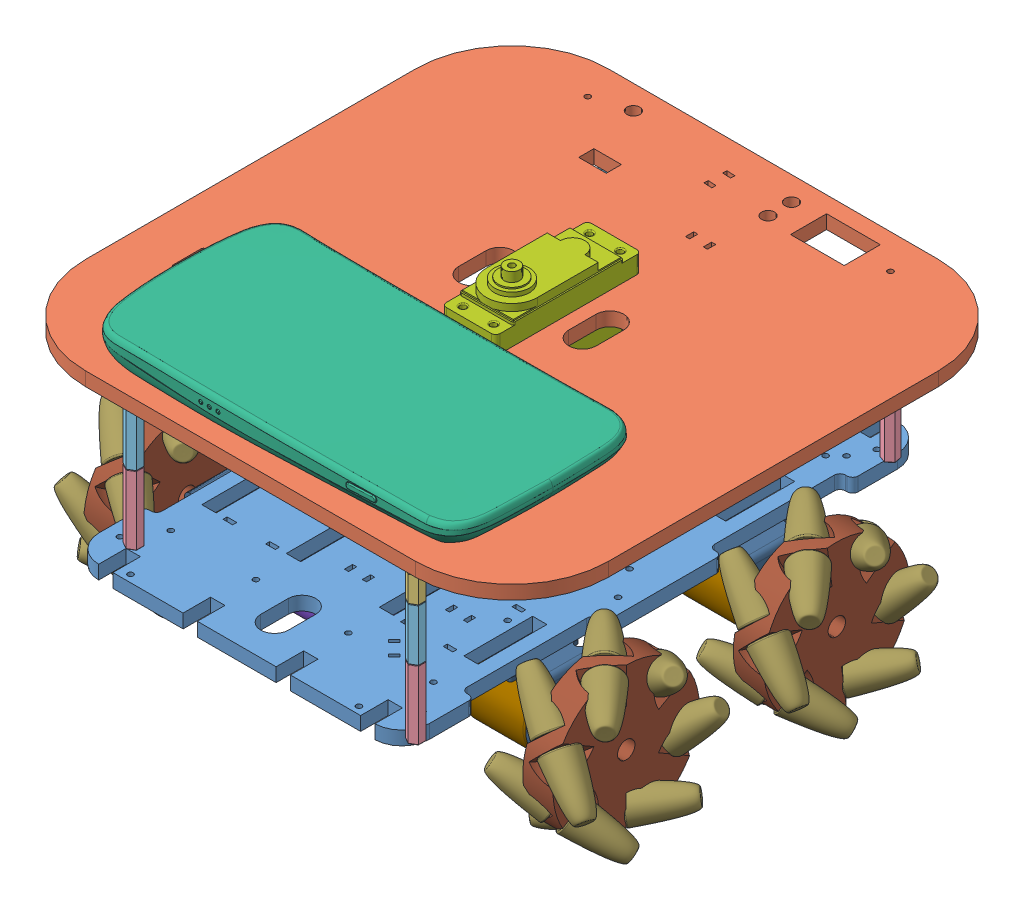
SolidWorks assembly Robo_01, configuration Valor predeterminado. Lengths in mm.
Overall size (202.63 132.58 190.5).
92 component instances, 12 part files, 61 mates.
Components (placement in the parent):
- Plataforma_1-1: Plataforma_1 [Valor predeterminado] at (-69.9818 -54.6704 16.9892) size (120 5 190)
- Plataforma_2-1: Plataforma_2 [Valor predeterminado] at (-104.9818 3.8296 16.9892) size (190 5 190)
- PC-Standoff - 9.5mm - FF-1: PC-Standoff - 9.5mm - FF [Valor predeterminado] at (-59.9818 -5.6704 -0.5108) x (0.866025 0 0.5) z (-0.5 0 0.866025) size (5.5 9.5 4.76)
- PC-Standoff - 9.5mm - FF-2: PC-Standoff - 9.5mm - FF [Valor predeterminado] at (52.5182 -5.6704 9.4892) x (0 0 1) z (-1 0 0) size (5.5 9.5 4.76)
- PC-Standoff - 9.5mm - FF-3: PC-Standoff - 9.5mm - FF [Valor predeterminado] at (-62.4818 -5.6704 -175.5108) x (0 0 1) z (-1 0 0) size (5.5 9.5 4.76)
- PC-Standoff - 9.5mm - FF-4: PC-Standoff - 9.5mm - FF [Valor predeterminado] at (50.0182 -5.6704 -165.5108) x (0.176181 0 0.984358) z (-0.984358 0 0.176181) size (5.5 9.5 4.76)
- PC-Standoff - 25mm-6: PC-Standoff - 25mm [Valor predeterminado] at (50.0182 -24.6704 -165.5108) x (-0.176181 0 -0.984358) z (-0.984358 0 0.176181) size (5.5 29.76 4.76)
- PC-Standoff - 19mm-6: PC-Standoff - 19mm [Valor predeterminado] at (50.0182 -5.6704 -165.5108) x (-0.176181 0 -0.984358) z (-0.984358 0 0.176181) size (5.5 23.76 4.76)
- PC-Standoff - 25mm-7: PC-Standoff - 25mm [Valor predeterminado] at (52.5182 -24.6704 9.4892) x (0 0 -1) z (-1 0 0) size (5.5 29.76 4.76)
- PC-Standoff - 19mm-7: PC-Standoff - 19mm [Valor predeterminado] at (52.5182 -5.6704 9.4892) x (0 0 -1) z (-1 0 0) size (5.5 23.76 4.76)
- PC-Standoff - 25mm-8: PC-Standoff - 25mm [Valor predeterminado] at (-59.9818 -24.6704 -0.5108) x (0 0 -1) z (-1 0 0) size (5.5 29.76 4.76)
- PC-Standoff - 19mm-8: PC-Standoff - 19mm [Valor predeterminado] at (-59.9818 -5.6704 -0.5108) x (0 0 -1) z (-1 0 0) size (5.5 23.76 4.76)
- PC-Standoff - 19mm-1: PC-Standoff - 19mm [Valor predeterminado] at (-62.4818 -5.6704 -175.5108) x (0 0 -1) z (-1 0 0) size (5.5 23.76 4.76)
- PC-Standoff - 25mm-1: PC-Standoff - 25mm [Valor predeterminado] at (-62.4818 -24.6704 -175.5108) x (0 0 -1) z (-1 0 0) size (5.5 29.76 4.76)
- Nexus-1: Nexus [Default] at (-34.6431 -20.5856 4.0062) x (0.001932 0 0.999998) z (0 1 0) size (78.79 147.01 23.11)
- Servo-HS-311-1: Servo-HS-311 [Default] at (5.0182 -16.5704 -73.4788) x (0 0 -1) z (1 0 0) size (52.83 41.27 19.56)
- Motor_com_suporte-1: Motor_com_suporte [Valor predeterminado] at (-43.7296 -69.2683 -124.4885) x (0 -0.561689 -0.827349) z (-1 0 0) size (35.57 35.97 69.3)
  - Motor-2: Motor [Valor predeterminado] at (3.672 0.435 -26.0477) size (25 25 69.3)
    - Motor-1: Motor [Valor predeterminado] at (-6.4714 0.7429 0) size (24.4 24.4 45.8)
    - Motor_Redutor-1: Motor_Redutor [Valor predeterminado] at (-6.4714 0.7429 30.8) size (25 25 33.5)
  - Suporte_Motor-1: Suporte_Motor [Valor predeterminado] at (-21.0049 -3.3839 29.2523) x (0.827349 -0.561689 0) z (0 0 1) size (25 26.5 51.5)
- Mecanum-1: Mecanum [Valor predeterminado] at (-89.6759 -62.9091 -126.9148) x (0 0.729357 -0.684133) z (0 -0.684133 -0.729357) size (63.95 43.87 68.72)
  - Mecanum_meio-1: Mecanum_meio [Valor predeterminado] at (-7.8992 -5.806 0) size (53.2 11 53.2)
  - Mecanum_wheel-1: Mecanum_wheel [Valor predeterminado] at (-15.5494 1.6585 20.3217) x (0.789069 -0.574225 -0.218256) z (-0.048689 -0.412632 0.909596) size (12.32 20.06 12.32)
  - Mecanum_wheel-2: Mecanum_wheel [Valor predeterminado] at (-29.3234 1.6585 3.5355) x (0.985157 -0.121379 0.121379) z (-0.171655 -0.696611 0.696611) size (12.32 20.06 12.32)
  - Mecanum_wheel-3: Mecanum_wheel [Valor predeterminado] at (-21.6732 1.6585 -16.7862) x (0.789069 0.51914 0.328426) z (-0.048689 -0.480097 0.875863) size (12.32 20.06 12.32)
  - Mecanum_wheel-4: Mecanum_wheel [Valor predeterminado] at (-0.2489 1.6585 -20.3217) x (0.789069 0.574225 -0.218256) z (-0.048689 0.412632 0.909596) size (12.32 20.06 12.32)
  - Mecanum_wheel-5: Mecanum_wheel [Valor predeterminado] at (13.5251 1.6585 -3.5355) x (0.91238 -0.28945 -0.28945) z (0.409344 0.64515 0.64515) size (12.32 20.06 12.32)
  - Mecanum_wheel-6: Mecanum_wheel [Valor predeterminado] at (5.8748 1.6585 16.7862) x (0.68106 -0.698943 -0.218256) z (0.401444 0.107137 0.909596) size (12.32 20.06 12.32)
  - Mecanum_wheel-8: Mecanum_wheel [Valor predeterminado] at (-29.3234 -1.5235 0.3536) x (1 0 0) z (0 0.707107 -0.707107) size (12.32 20.06 12.32)
  - Mecanum_wheel-9: Mecanum_wheel [Valor predeterminado] at (-18.3051 -1.5235 18.7308) x (0.785714 -0.494872 -0.371154) z (-0.087482 0.505076 -0.85863) size (12.32 20.06 12.32)
  - Mecanum_wheel-10: Mecanum_wheel [Valor predeterminado] at (3.1192 -1.5235 18.3772) x (0.7 -0.69282 -0.173205) z (-0.367423 -0.141421 -0.919239) size (12.32 20.06 12.32)
  - Mecanum_wheel-11: Mecanum_wheel [Valor predeterminado] at (13.5251 -1.5235 -0.3536) x (1 0 0) z (0 -0.707107 -0.707107) size (12.32 20.06 12.32)
  - Mecanum_wheel-12: Mecanum_wheel [Valor predeterminado] at (2.5068 -1.5235 -18.7308) x (0.7 0.69282 0.173205) z (0.367423 -0.141421 -0.919239) size (12.32 20.06 12.32)
  - Mecanum_wheel-13: Mecanum_wheel [Valor predeterminado] at (-18.9175 -1.5235 -18.3772) x (0.785714 0.494872 0.371154) z (0.087482 0.505076 -0.85863) size (12.32 20.06 12.32)
- Motor_com_suporte-2: Motor_com_suporte [Valor predeterminado] at (-43.7296 -69.2683 -47.4885) x (0 -0.561689 -0.827349) z (-1 0 0) size (35.57 35.97 69.3)
  - Motor-2: Motor [Valor predeterminado] at (3.672 0.435 -26.0477) size (25 25 69.3)
    - Motor-1: Motor [Valor predeterminado] at (-6.4714 0.7429 0) size (24.4 24.4 45.8)
    - Motor_Redutor-1: Motor_Redutor [Valor predeterminado] at (-6.4714 0.7429 30.8) size (25 25 33.5)
  - Suporte_Motor-1: Suporte_Motor [Valor predeterminado] at (-21.0049 -3.3839 29.2523) x (0.827349 -0.561689 0) z (0 0 1) size (25 26.5 51.5)
- Mecanum-2: Mecanum [Valor predeterminado] at (-89.6759 -66.4607 -52.0946) x (0 0.279735 -0.960077) z (0 -0.960077 -0.279735) size (63.95 43.87 68.72)
  - Mecanum_meio-1: Mecanum_meio [Valor predeterminado] at (-7.8992 -5.806 0) size (53.2 11 53.2)
  - Mecanum_wheel-1: Mecanum_wheel [Valor predeterminado] at (-15.5494 1.6585 20.3217) x (0.789069 -0.574225 -0.218256) z (-0.048689 -0.412632 0.909596) size (12.32 20.06 12.32)
  - Mecanum_wheel-2: Mecanum_wheel [Valor predeterminado] at (-29.3234 1.6585 3.5355) x (0.985157 -0.121379 0.121379) z (-0.171655 -0.696611 0.696611) size (12.32 20.06 12.32)
  - Mecanum_wheel-3: Mecanum_wheel [Valor predeterminado] at (-21.6732 1.6585 -16.7862) x (0.789069 0.51914 0.328426) z (-0.048689 -0.480097 0.875863) size (12.32 20.06 12.32)
  - Mecanum_wheel-4: Mecanum_wheel [Valor predeterminado] at (-0.2489 1.6585 -20.3217) x (0.789069 0.574225 -0.218256) z (-0.048689 0.412632 0.909596) size (12.32 20.06 12.32)
  - Mecanum_wheel-5: Mecanum_wheel [Valor predeterminado] at (13.5251 1.6585 -3.5355) x (0.91238 -0.28945 -0.28945) z (0.409344 0.64515 0.64515) size (12.32 20.06 12.32)
  - Mecanum_wheel-6: Mecanum_wheel [Valor predeterminado] at (5.8748 1.6585 16.7862) x (0.68106 -0.698943 -0.218256) z (0.401444 0.107137 0.909596) size (12.32 20.06 12.32)
  - Mecanum_wheel-8: Mecanum_wheel [Valor predeterminado] at (-29.3234 -1.5235 0.3536) x (1 0 0) z (0 0.707107 -0.707107) size (12.32 20.06 12.32)
  - Mecanum_wheel-9: Mecanum_wheel [Valor predeterminado] at (-18.3051 -1.5235 18.7308) x (0.785714 -0.494872 -0.371154) z (-0.087482 0.505076 -0.85863) size (12.32 20.06 12.32)
  - Mecanum_wheel-10: Mecanum_wheel [Valor predeterminado] at (3.1192 -1.5235 18.3772) x (0.7 -0.69282 -0.173205) z (-0.367423 -0.141421 -0.919239) size (12.32 20.06 12.32)
  - Mecanum_wheel-11: Mecanum_wheel [Valor predeterminado] at (13.5251 -1.5235 -0.3536) x (1 0 0) z (0 -0.707107 -0.707107) size (12.32 20.06 12.32)
  - Mecanum_wheel-12: Mecanum_wheel [Valor predeterminado] at (2.5068 -1.5235 -18.7308) x (0.7 0.69282 0.173205) z (0.367423 -0.141421 -0.919239) size (12.32 20.06 12.32)
  - Mecanum_wheel-13: Mecanum_wheel [Valor predeterminado] at (-18.9175 -1.5235 -18.3772) x (0.785714 0.494872 0.371154) z (0.087482 0.505076 -0.85863) size (12.32 20.06 12.32)
- Mecanum-7: Mecanum [Valor predeterminado] at (69.2122 -73.799 -38.5029) x (0 -0.649254 0.760572) z (0 -0.760572 -0.649254) size (63.95 43.87 68.72)
  - Mecanum_meio-1: Mecanum_meio [Valor predeterminado] at (-7.8992 -5.806 0) size (53.2 11 53.2)
  - Mecanum_wheel-1: Mecanum_wheel [Valor predeterminado] at (-15.5494 1.6585 20.3217) x (0.789069 -0.574225 -0.218256) z (-0.048689 -0.412632 0.909596) size (12.32 20.06 12.32)
  - Mecanum_wheel-2: Mecanum_wheel [Valor predeterminado] at (-29.3234 1.6585 3.5355) x (0.985157 -0.121379 0.121379) z (-0.171655 -0.696611 0.696611) size (12.32 20.06 12.32)
  - Mecanum_wheel-3: Mecanum_wheel [Valor predeterminado] at (-21.6732 1.6585 -16.7862) x (0.789069 0.51914 0.328426) z (-0.048689 -0.480097 0.875863) size (12.32 20.06 12.32)
  - Mecanum_wheel-4: Mecanum_wheel [Valor predeterminado] at (-0.2489 1.6585 -20.3217) x (0.789069 0.574225 -0.218256) z (-0.048689 0.412632 0.909596) size (12.32 20.06 12.32)
  - Mecanum_wheel-5: Mecanum_wheel [Valor predeterminado] at (13.5251 1.6585 -3.5355) x (0.91238 -0.28945 -0.28945) z (0.409344 0.64515 0.64515) size (12.32 20.06 12.32)
  - Mecanum_wheel-6: Mecanum_wheel [Valor predeterminado] at (5.8748 1.6585 16.7862) x (0.68106 -0.698943 -0.218256) z (0.401444 0.107137 0.909596) size (12.32 20.06 12.32)
  - Mecanum_wheel-8: Mecanum_wheel [Valor predeterminado] at (-29.3234 -1.5235 0.3536) x (1 0 0) z (0 0.707107 -0.707107) size (12.32 20.06 12.32)
  - Mecanum_wheel-9: Mecanum_wheel [Valor predeterminado] at (-18.3051 -1.5235 18.7308) x (0.785714 -0.494872 -0.371154) z (-0.087482 0.505076 -0.85863) size (12.32 20.06 12.32)
  - Mecanum_wheel-10: Mecanum_wheel [Valor predeterminado] at (3.1192 -1.5235 18.3772) x (0.7 -0.69282 -0.173205) z (-0.367423 -0.141421 -0.919239) size (12.32 20.06 12.32)
  - Mecanum_wheel-11: Mecanum_wheel [Valor predeterminado] at (13.5251 -1.5235 -0.3536) x (1 0 0) z (0 -0.707107 -0.707107) size (12.32 20.06 12.32)
  - Mecanum_wheel-12: Mecanum_wheel [Valor predeterminado] at (2.5068 -1.5235 -18.7308) x (0.7 0.69282 0.173205) z (0.367423 -0.141421 -0.919239) size (12.32 20.06 12.32)
  - Mecanum_wheel-13: Mecanum_wheel [Valor predeterminado] at (-18.9175 -1.5235 -18.3772) x (0.785714 0.494872 0.371154) z (0.087482 0.505076 -0.85863) size (12.32 20.06 12.32)
- Motor_com_suporte-7: Motor_com_suporte [Valor predeterminado] at (23.2659 -69.2683 -41.533) x (0 -0.561689 0.827349) z (1 0 0) size (35.57 35.97 69.3)
  - Motor-2: Motor [Valor predeterminado] at (3.672 0.435 -26.0477) size (25 25 69.3)
    - Motor-1: Motor [Valor predeterminado] at (-6.4714 0.7429 0) size (24.4 24.4 45.8)
    - Motor_Redutor-1: Motor_Redutor [Valor predeterminado] at (-6.4714 0.7429 30.8) size (25 25 33.5)
  - Suporte_Motor-1: Suporte_Motor [Valor predeterminado] at (-21.0049 -3.3839 29.2523) x (0.827349 -0.561689 0) z (0 0 1) size (25 26.5 51.5)
- Mecanum-11: Mecanum [Valor predeterminado] at (68.7122 -61.1594 -119.0649) x (0 0.950856 0.309633) z (0 -0.309633 0.950856) size (63.95 43.87 68.72)
  - Mecanum_meio-1: Mecanum_meio [Valor predeterminado] at (-7.8992 -5.806 0) size (53.2 11 53.2)
  - Mecanum_wheel-1: Mecanum_wheel [Valor predeterminado] at (-15.5494 1.6585 20.3217) x (0.789069 -0.574225 -0.218256) z (-0.048689 -0.412632 0.909596) size (12.32 20.06 12.32)
  - Mecanum_wheel-2: Mecanum_wheel [Valor predeterminado] at (-29.3234 1.6585 3.5355) x (0.985157 -0.121379 0.121379) z (-0.171655 -0.696611 0.696611) size (12.32 20.06 12.32)
  - Mecanum_wheel-3: Mecanum_wheel [Valor predeterminado] at (-21.6732 1.6585 -16.7862) x (0.789069 0.51914 0.328426) z (-0.048689 -0.480097 0.875863) size (12.32 20.06 12.32)
  - Mecanum_wheel-4: Mecanum_wheel [Valor predeterminado] at (-0.2489 1.6585 -20.3217) x (0.789069 0.574225 -0.218256) z (-0.048689 0.412632 0.909596) size (12.32 20.06 12.32)
  - Mecanum_wheel-5: Mecanum_wheel [Valor predeterminado] at (13.5251 1.6585 -3.5355) x (0.91238 -0.28945 -0.28945) z (0.409344 0.64515 0.64515) size (12.32 20.06 12.32)
  - Mecanum_wheel-6: Mecanum_wheel [Valor predeterminado] at (5.8748 1.6585 16.7862) x (0.68106 -0.698943 -0.218256) z (0.401444 0.107137 0.909596) size (12.32 20.06 12.32)
  - Mecanum_wheel-8: Mecanum_wheel [Valor predeterminado] at (-29.3234 -1.5235 0.3536) x (1 0 0) z (0 0.707107 -0.707107) size (12.32 20.06 12.32)
  - Mecanum_wheel-9: Mecanum_wheel [Valor predeterminado] at (-18.3051 -1.5235 18.7308) x (0.785714 -0.494872 -0.371154) z (-0.087482 0.505076 -0.85863) size (12.32 20.06 12.32)
  - Mecanum_wheel-10: Mecanum_wheel [Valor predeterminado] at (3.1192 -1.5235 18.3772) x (0.7 -0.69282 -0.173205) z (-0.367423 -0.141421 -0.919239) size (12.32 20.06 12.32)
  - Mecanum_wheel-11: Mecanum_wheel [Valor predeterminado] at (13.5251 -1.5235 -0.3536) x (1 0 0) z (0 -0.707107 -0.707107) size (12.32 20.06 12.32)
  - Mecanum_wheel-12: Mecanum_wheel [Valor predeterminado] at (2.5068 -1.5235 -18.7308) x (0.7 0.69282 0.173205) z (0.367423 -0.141421 -0.919239) size (12.32 20.06 12.32)
  - Mecanum_wheel-13: Mecanum_wheel [Valor predeterminado] at (-18.9175 -1.5235 -18.3772) x (0.785714 0.494872 0.371154) z (0.087482 0.505076 -0.85863) size (12.32 20.06 12.32)
- Motor_com_suporte-11: Motor_com_suporte [Valor predeterminado] at (22.7659 -69.2683 -118.533) x (0 -0.561689 0.827349) z (1 0 0) size (35.57 35.97 69.3)
  - Motor-2: Motor [Valor predeterminado] at (3.672 0.435 -26.0477) size (25 25 69.3)
    - Motor-1: Motor [Valor predeterminado] at (-6.4714 0.7429 0) size (24.4 24.4 45.8)
    - Motor_Redutor-1: Motor_Redutor [Valor predeterminado] at (-6.4714 0.7429 30.8) size (25 25 33.5)
  - Suporte_Motor-1: Suporte_Motor [Valor predeterminado] at (-21.0049 -3.3839 29.2523) x (0.827349 -0.561689 0) z (0 0 1) size (25 26.5 51.5)
Mates (geometry in assembly coordinates):
- Coincidente1: coincident anti-aligned: plane of Plataforma_1-1 through (-69.9818 -49.6704 -178.0108) normal (0 1 0); plane of PC-Standoff - 25mm-1 through (-62.4818 -49.6704 -178.259) normal (0 -1 0)
- Coincidente3: coincident anti-aligned: plane of PC-Standoff - 19mm-1 through (-62.4818 -24.6704 -178.259) normal (0 -1 0); plane of PC-Standoff - 25mm-1 through (-62.4818 -24.6704 -178.259) normal (0 1 0)
- Concêntrico2: concentric aligned: cylinder of PC-Standoff - 19mm-1 through (-62.4818 -19.9104 -175.5108) axis (0 -1 0) radius 1.0922; cylinder of PC-Standoff - 25mm-1 through (-62.4818 -19.9104 -175.5108) axis (0 -1 0) radius 1.0922
- Coincidente4: coincident aligned: plane of PC-Standoff - 19mm-1 through (-62.4818 -5.6704 -175.5108) normal (-1 0 0); plane of PC-Standoff - 25mm-1 through (-62.4818 -24.6704 -175.5108) normal (-1 0 0)
- Coincidente13: coincident anti-aligned: plane of PC-Standoff - 25mm-6 through (49.534 -24.6704 -168.216) normal (0 1 0); plane of PC-Standoff - 19mm-6 through (49.534 -24.6704 -168.216) normal (0 -1 0)
- Concêntrico11: concentric aligned: cylinder of PC-Standoff - 25mm-6 through (50.0182 -19.9104 -165.5108) axis (0 -1 0) radius 1.0922; cylinder of PC-Standoff - 19mm-6 through (50.0182 -19.9104 -165.5108) axis (0 -1 0) radius 1.0922
- Coincidente14: coincident aligned: plane of PC-Standoff - 25mm-6 through (50.0182 -24.6704 -165.5108) normal (-0.984358 0 0.176181); plane of PC-Standoff - 19mm-6 through (50.0182 -5.6704 -165.5108) normal (-0.984358 0 0.176181)
- Coincidente15: coincident anti-aligned: plane of Plataforma_1-1 through (-69.9818 -49.6704 -178.0108) normal (0 1 0); plane of PC-Standoff - 25mm-6 through (49.534 -49.6704 -168.216) normal (0 -1 0)
- Coincidente16: coincident anti-aligned: plane of PC-Standoff - 25mm-7 through (52.5182 -24.6704 6.741) normal (0 1 0); plane of PC-Standoff - 19mm-7 through (52.5182 -24.6704 6.741) normal (0 -1 0)
- Concêntrico13: concentric aligned: cylinder of PC-Standoff - 25mm-7 through (52.5182 -19.9104 9.4892) axis (0 -1 0) radius 1.0922; cylinder of PC-Standoff - 19mm-7 through (52.5182 -19.9104 9.4892) axis (0 -1 0) radius 1.0922
- Coincidente17: coincident aligned: plane of PC-Standoff - 25mm-7 through (52.5182 -24.6704 9.4892) normal (-1 0 0); plane of PC-Standoff - 19mm-7 through (52.5182 -5.6704 9.4892) normal (-1 0 0)
- Coincidente18: coincident anti-aligned: plane of Plataforma_1-1 through (-69.9818 -49.6704 -178.0108) normal (0 1 0); plane of PC-Standoff - 25mm-7 through (52.5182 -49.6704 6.741) normal (0 -1 0)
- Coincidente19: coincident anti-aligned: plane of PC-Standoff - 25mm-8 through (-59.9818 -24.6704 -3.259) normal (0 1 0); plane of PC-Standoff - 19mm-8 through (-59.9818 -24.6704 -3.259) normal (0 -1 0)
- Concêntrico15: concentric aligned: cylinder of PC-Standoff - 25mm-8 through (-59.9818 -19.9104 -0.5108) axis (0 -1 0) radius 1.0922; cylinder of PC-Standoff - 19mm-8 through (-59.9818 -19.9104 -0.5108) axis (0 -1 0) radius 1.0922
- Coincidente20: coincident aligned: plane of PC-Standoff - 25mm-8 through (-59.9818 -24.6704 -0.5108) normal (-1 0 0); plane of PC-Standoff - 19mm-8 through (-59.9818 -5.6704 -0.5108) normal (-1 0 0)
- Coincidente21: coincident anti-aligned: plane of Plataforma_1-1 through (-69.9818 -49.6704 -178.0108) normal (0 1 0); plane of PC-Standoff - 25mm-8 through (-59.9818 -49.6704 -3.259) normal (0 -1 0)
- Concêntrico17: concentric: cylinder of Plataforma_1-1 through (-62.4818 -54.6704 9.4892) axis (0 1 0) radius 1; cylinder of PC-Standoff - 25mm-8 through (-62.4818 -44.9104 9.4892) axis (0 -1 0) radius 1.0922
- Concêntrico18: concentric: cylinder of Plataforma_1-1 through (-62.4818 -54.6704 -175.5108) axis (0 1 0) radius 1; cylinder of PC-Standoff - 25mm-1 through (-62.4818 -44.9104 -175.5108) axis (0 -1 0) radius 1.0922
- Concêntrico19: concentric: cylinder of Plataforma_1-1 through (52.5182 -54.6704 -175.5108) axis (0 1 0) radius 1; cylinder of PC-Standoff - 25mm-6 through (52.5182 -44.9104 -175.5108) axis (0 -1 0) radius 1.0922
- Concêntrico20: concentric: cylinder of Plataforma_1-1 through (52.5182 -54.6704 9.4892) axis (0 1 0) radius 1; cylinder of PC-Standoff - 25mm-7 through (52.5182 -44.9104 9.4892) axis (0 -1 0) radius 1.0922
- Coincidente25: coincident anti-aligned: plane of Plataforma_2-1 through (5.0182 3.8296 -114.1108) normal (-1 0 0); plane of Servo-HS-311-1 through (5.0182 16.7036 -73.4788) normal (1 0 0)
- Distância1: distance = 0.5 mm anti-aligned: plane of Plataforma_2-1 through (-14.9818 3.8296 -114.1108) normal (0 0 1); plane of Servo-HS-311-1 through (5.0182 16.7036 -113.6108) normal (0 0 -1)
- Coincidente27: coincident anti-aligned: plane of Plataforma_2-1 through (-99.9818 8.8296 -178.0108) normal (0 1 0); plane of Servo-HS-311-1 through (5.0182 8.8296 -119.9608) normal (0 -1 0)
- Coincidente28: coincident anti-aligned: plane of Plataforma_2-1 through (-99.9818 8.8296 -178.0108) normal (0 1 0); plane of Nexus-1 through (44.6823 8.8296 -27.988) normal (0 -1 0)
- Concêntrico21: concentric anti-aligned: cylinder of PC-Standoff - 19mm-8 through (-59.9818 -0.9104 -0.5108) axis (0 -1 0) radius 1.0922; cylinder of PC-Standoff - 9.5mm - FF-1 through (-59.9818 -0.9304 -0.5108) axis (0 1 0) radius 1.0922
- Coincidente29: coincident anti-aligned: plane of PC-Standoff - 19mm-8 through (-59.9818 -5.6704 -3.259) normal (0 1 0); plane of PC-Standoff - 9.5mm - FF-1 through (-57.6018 -5.6704 0.8633) normal (0 -1 0)
- Coincidente30: coincident aligned: plane of PC-Standoff - 19mm-8 through (-59.9818 -24.6704 2.2374) normal (-0.5 0 0.866025); plane of PC-Standoff - 9.5mm - FF-1 through (-62.3618 3.8296 0.8633) normal (-0.5 0 0.866025)
- Concêntrico22: concentric anti-aligned: cylinder of PC-Standoff - 19mm-7 through (52.5182 -0.9104 9.4892) axis (0 -1 0) radius 1.0922; cylinder of PC-Standoff - 9.5mm - FF-2 through (52.5182 -0.9304 9.4892) axis (0 1 0) radius 1.0922
- Coincidente31: coincident anti-aligned: plane of PC-Standoff - 19mm-7 through (52.5182 -5.6704 6.741) normal (0 1 0); plane of PC-Standoff - 9.5mm - FF-2 through (52.5182 -5.6704 12.2374) normal (0 -1 0)
- Coincidente32: coincident aligned: plane of PC-Standoff - 19mm-7 through (50.1382 -24.6704 10.8633) normal (-1 0 0); plane of PC-Standoff - 9.5mm - FF-2 through (50.1382 3.8296 8.1151) normal (-1 0 0)
- Concêntrico23: concentric anti-aligned: cylinder of PC-Standoff - 19mm-1 through (-62.4818 -0.9104 -175.5108) axis (0 -1 0) radius 1.0922; cylinder of PC-Standoff - 9.5mm - FF-3 through (-62.4818 -0.9304 -175.5108) axis (0 1 0) radius 1.0922
- Coincidente33: coincident anti-aligned: plane of PC-Standoff - 19mm-1 through (-62.4818 -5.6704 -178.259) normal (0 1 0); plane of PC-Standoff - 9.5mm - FF-3 through (-62.4818 -5.6704 -172.7626) normal (0 -1 0)
- Coincidente34: coincident aligned: plane of PC-Standoff - 19mm-1 through (-64.8618 -24.6704 -174.1367) normal (-1 0 0); plane of PC-Standoff - 9.5mm - FF-3 through (-64.8618 3.8296 -176.8849) normal (-1 0 0)
- Concêntrico24: concentric anti-aligned: cylinder of PC-Standoff - 19mm-6 through (50.0182 -0.9104 -165.5108) axis (0 -1 0) radius 1.0922; cylinder of PC-Standoff - 9.5mm - FF-4 through (50.0182 -0.9304 -165.5108) axis (0 1 0) radius 1.0922
- Coincidente36: coincident anti-aligned: plane of PC-Standoff - 19mm-6 through (49.534 -5.6704 -168.216) normal (0 1 0); plane of PC-Standoff - 9.5mm - FF-4 through (50.5024 -5.6704 -162.8056) normal (0 -1 0)
- Coincidente37: coincident aligned: plane of PC-Standoff - 19mm-6 through (47.9175 -24.6704 -163.7389) normal (-0.984358 0 0.176181); plane of PC-Standoff - 9.5mm - FF-4 through (47.4333 3.8296 -166.4441) normal (-0.984358 0 0.176181)
- Concêntrico25: concentric aligned: cylinder of Plataforma_2-1 through (-59.9818 3.8296 -0.5108) axis (0 1 0) radius 1; cylinder of PC-Standoff - 9.5mm - FF-1 through (-59.9818 -0.9304 -0.5108) axis (0 1 0) radius 1.0922
- Concêntrico26: concentric aligned: cylinder of Plataforma_2-1 through (50.0182 3.8296 -165.5108) axis (0 1 0) radius 1; cylinder of PC-Standoff - 9.5mm - FF-4 through (50.0182 -0.9304 -165.5108) axis (0 1 0) radius 1.0922
- Coincidente38: coincident anti-aligned: plane of Plataforma_2-1 through (-99.9818 3.8296 -178.0108) normal (0 -1 0); plane of PC-Standoff - 9.5mm - FF-1 through (-57.6018 3.8296 0.8633) normal (0 1 0)
- Coincidente39: coincident anti-aligned: plane of Plataforma_1-1 through (-69.9818 -54.6704 -178.0108) normal (0 -1 0); plane of Motor_com_suporte-1/Suporte_Motor-1 through (-21.4818 -54.6704 -109.0108) normal (0 1 0)
- Concêntrico27: concentric aligned: cylinder of Motor_com_suporte-1/Motor-2/Motor_Redutor-1 through (-81.9818 -68.6704 -121.5108) axis (1 0 0) radius 2; cylinder of Mecanum-1/Mecanum_meio-1 through (-95.4818 -68.6704 -121.5108) axis (1 0 0) radius 3.175
- Coincidente41: coincident anti-aligned: plane of Plataforma_1-1 through (-69.9818 -54.6704 -178.0108) normal (0 -1 0); plane of Motor_com_suporte-1/Suporte_Motor-1 through (-21.4818 -54.6704 -109.0108) normal (0 1 0)
- Distância4: distance = 3 mm aligned: plane of Motor_com_suporte-1/Suporte_Motor-1 through (-72.9818 -56.1704 -109.0108) normal (-1 0 0); plane of Plataforma_1-1 through (-69.9818 -49.6704 11.9892) normal (-1 0 0)
- Coincidente45: coincident anti-aligned: plane of Plataforma_1-1 through (-69.9818 -54.6704 -178.0108) normal (0 -1 0); plane of Motor_com_suporte-2/Suporte_Motor-1 through (-21.4818 -54.6704 -32.0108) normal (0 1 0)
- Coincidente46: coincident anti-aligned: plane of Plataforma_1-1 through (-69.9818 -54.6704 -178.0108) normal (0 -1 0); plane of Motor_com_suporte-2/Suporte_Motor-1 through (-21.4818 -54.6704 -32.0108) normal (0 1 0)
- Distância5: distance = 3 mm aligned: plane of Motor_com_suporte-2/Suporte_Motor-1 through (-72.9818 -56.1704 -32.0108) normal (-1 0 0); plane of Plataforma_1-1 through (-69.9818 -49.6704 11.9892) normal (-1 0 0)
- Concêntrico28: concentric aligned: cylinder of Motor_com_suporte-2/Motor-2/Motor_Redutor-1 through (-81.9818 -68.6704 -44.5108) axis (1 0 0) radius 2; cylinder of Mecanum-2/Mecanum_meio-1 through (-95.4818 -68.6704 -44.5108) axis (1 0 0) radius 3.175
- Distância6: distance = 44 mm aligned: plane of Motor_com_suporte-2/Suporte_Motor-1 through (-72.9818 -56.1704 -32.0108) normal (0 0 1); plane of Plataforma_1-1 through (-69.9818 -49.6704 11.9892) normal (0 0 1)
- Distância7: distance = 44 mm aligned: plane of Motor_com_suporte-1/Suporte_Motor-1 through (-72.9818 -56.1704 -134.0108) normal (0 0 -1); plane of Plataforma_1-1 through (-69.9818 -49.6704 -178.0108) normal (0 0 -1)
- Distância8: distance = 2.5 mm anti-aligned: plane of Mecanum-2/Mecanum_meio-1 through (-84.4818 -68.6704 -44.5108) normal (1 0 0); plane of Motor_com_suporte-2/Motor-2/Motor_Redutor-1 through (-81.9818 -68.6704 -44.5108) normal (-1 0 0)
- Distância9: distance = 2.5 mm anti-aligned: plane of Motor_com_suporte-1/Motor-2/Motor_Redutor-1 through (-81.9818 -68.6704 -121.5108) normal (-1 0 0); plane of Mecanum-1/Mecanum_meio-1 through (-84.4818 -68.6704 -121.5108) normal (1 0 0)
- Concêntrico33: concentric aligned: cylinder of Mecanum-7/Mecanum_meio-1 through (75.0182 -68.6704 -44.5108) axis (-1 0 0) radius 3.175; cylinder of Motor_com_suporte-7/Motor-2/Motor_Redutor-1 through (61.5182 -68.6704 -44.5108) axis (-1 0 0) radius 2
- Distância21: distance = 2.5 mm anti-aligned: plane of Mecanum-7/Mecanum_meio-1 through (64.0182 -68.6704 -44.5108) normal (-1 0 0); plane of Motor_com_suporte-7/Motor-2/Motor_Redutor-1 through (61.5182 -68.6704 -44.5108) normal (1 0 0)
- Coincidente57: coincident anti-aligned: plane of Plataforma_1-1 through (-69.9818 -54.6704 -178.0108) normal (0 -1 0); plane of Motor_com_suporte-7/Suporte_Motor-1 through (1.0182 -54.6704 -57.0108) normal (0 1 0)
- Distância23: distance = 44 mm aligned: plane of Motor_com_suporte-7/Suporte_Motor-1 through (52.5182 -56.1704 -32.0108) normal (0 0 1); plane of Plataforma_1-1 through (-69.9818 -49.6704 11.9892) normal (0 0 1)
- Distância24: distance = 2.5 mm aligned: plane of Motor_com_suporte-7/Suporte_Motor-1 through (52.5182 -56.1704 -57.0108) normal (1 0 0); plane of Plataforma_1-1 through (50.0182 -49.6704 11.9892) normal (1 0 0)
- Concêntrico37: concentric aligned: cylinder of Mecanum-11/Mecanum_meio-1 through (74.5182 -68.6704 -121.5108) axis (-1 0 0) radius 3.175; cylinder of Motor_com_suporte-11/Motor-2/Motor_Redutor-1 through (61.0182 -68.6704 -121.5108) axis (-1 0 0) radius 2
- Distância32: distance = 2.5 mm anti-aligned: plane of Mecanum-11/Mecanum_meio-1 through (63.5182 -68.6704 -121.5108) normal (-1 0 0); plane of Motor_com_suporte-11/Motor-2/Motor_Redutor-1 through (61.0182 -68.6704 -121.5108) normal (1 0 0)
- Coincidente66: coincident anti-aligned: plane of Plataforma_1-1 through (-69.9818 -54.6704 -178.0108) normal (0 -1 0); plane of Motor_com_suporte-11/Suporte_Motor-1 through (0.5182 -54.6704 -134.0108) normal (0 1 0)
- Distância35: distance = 2 mm aligned: plane of Motor_com_suporte-11/Suporte_Motor-1 through (52.0182 -56.1704 -134.0108) normal (1 0 0); plane of Plataforma_1-1 through (50.0182 -49.6704 11.9892) normal (1 0 0)
- Distância36: distance = 44 mm aligned: plane of Motor_com_suporte-11/Suporte_Motor-1 through (52.0182 -56.1704 -134.0108) normal (0 0 -1); plane of Plataforma_1-1 through (-69.9818 -49.6704 -178.0108) normal (0 0 -1)
